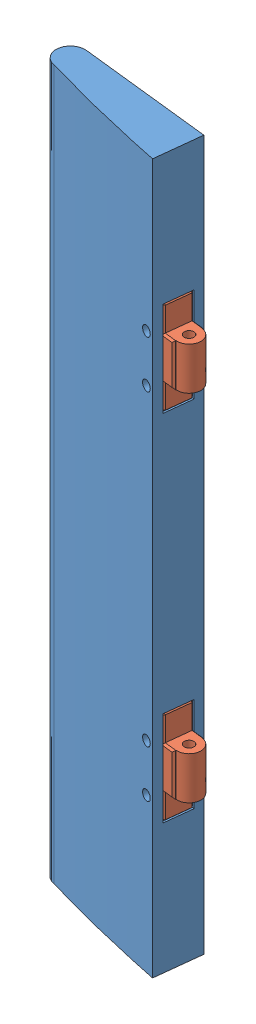
SolidWorks assembly Left_Aileron.STL, configuration Default. Lengths in mm.
Overall size (91.66 381 32.74).
3 component instances, 2 part files, 6 mates.
Components (placement in the parent):
- Wing_Aileron-6: Wing_Aileron [Default] at (-197.21 695.2 177.76) x (-1 0 0) z (0 1 0) size (79.56 32.74 381)
- Wing_to_Aileron_Wing_Piece-5: Wing_to_Aileron_Wing_Piece [Default] at (-282.5823 599.95 161.8643) x (0 -1 0) z (-0.110554 0 0.99387) size (50.8 21.17 15)
- Wing_to_Aileron_Wing_Piece-6: Wing_to_Aileron_Wing_Piece [Default] at (-282.5823 790.45 161.8643) x (0 -1 0) z (-0.110554 0 0.99387) size (50.8 21.17 15)
Mates (geometry in assembly coordinates):
- Concentric6: concentric aligned: cylinder of Wing_Aileron-6 through (-274.5901 612.65 128.3072) axis (-0.110554 0 0.99387) radius 2.65; cylinder of Wing_to_Aileron_Wing_Piece-5 through (-278.3749 612.65 162.3323) axis (-0.110554 0 0.99387) radius 2.65
- Concentric7: concentric aligned: cylinder of Wing_Aileron-6 through (-274.5901 587.25 128.3072) axis (-0.110554 0 0.99387) radius 2.65; cylinder of Wing_to_Aileron_Wing_Piece-5 through (-278.3749 587.25 162.3323) axis (-0.110554 0 0.99387) radius 2.65
- Width3: width aligned: plane of Wing_to_Aileron_Wing_Piece-5 through (-284.2406 599.95 176.7724) normal (-0.110554 0 0.99387); plane of Wing_Aileron-6 through (-282.5823 599.95 161.8643) normal (0.110554 0 -0.99387); plane of Wing_to_Aileron_Wing_Piece-5 through (-282.5839 574.55 161.8641) normal (-0.110554 0 0.99387); plane of Wing_Aileron-6 through (-284.2422 574.55 176.7722) normal (0.110554 0 -0.99387)
- Concentric8: concentric aligned: cylinder of Wing_Aileron-6 through (-274.5901 803.15 128.3072) axis (-0.110554 0 0.99387) radius 2.65; cylinder of Wing_to_Aileron_Wing_Piece-6 through (-278.3749 803.15 162.3323) axis (-0.110554 0 0.99387) radius 2.65
- Concentric9: concentric aligned: cylinder of Wing_Aileron-6 through (-274.5901 777.75 128.3072) axis (-0.110554 0 0.99387) radius 2.65; cylinder of Wing_to_Aileron_Wing_Piece-6 through (-278.3749 777.75 162.3323) axis (-0.110554 0 0.99387) radius 2.65
- Width4: width anti-aligned: plane of Wing_to_Aileron_Wing_Piece-6 through (-284.2406 790.45 176.7724) normal (-0.110554 0 0.99387); plane of Wing_Aileron-6 through (-282.5823 790.45 161.8643) normal (0.110554 0 -0.99387); plane of Wing_to_Aileron_Wing_Piece-6 through (-284.2422 765.05 176.7722) normal (0.110554 0 -0.99387); plane of Wing_Aileron-6 through (-282.5839 765.05 161.8641) normal (-0.110554 0 0.99387)
